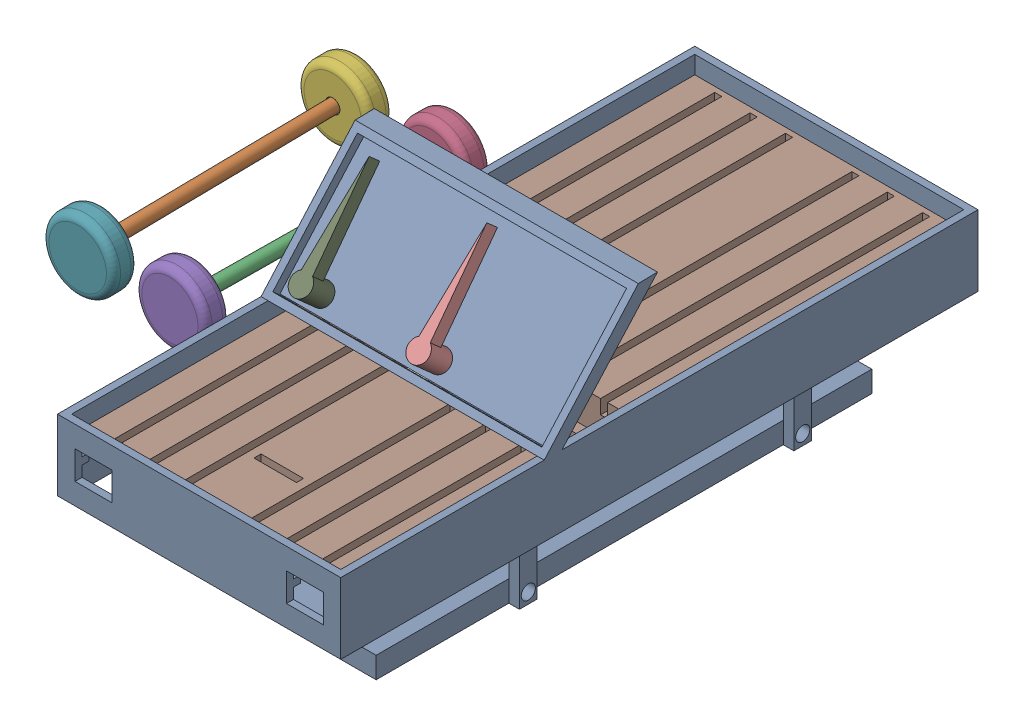
SolidWorks assembly SomeAssemblySmartPorch, configuration Default. Lengths in mm.
Overall size (178.29 89.34 228.6).
10 component instances, 5 part files, 13 mates.
Components (placement in the parent):
- CarBodySmartPorch-1: CarBodySmartPorch [Default] at (-89.7338 -29.1882 67.1813) size (101.6 88.9 228.6)
- AxleSmartPorch-1: AxleSmartPorch [Default] at (-198.0073 -16.2523 -0.0444) x (-0.855372 0.517873 0.012113) z (-0.013035 0.001859 -0.999913) size (4.57 4.57 96.52)
- AxleSmartPorch-2: AxleSmartPorch [Default] at (-163.9538 -16.0285 -96.7463) x (-0.659648 0.751544 -0.006868) z (-0.011251 -0.000737 0.999936) size (4.57 4.57 96.52)
- WheelSmartPorch-1: WheelSmartPorch [Default] at (-164.0253 -16.0332 -90.3967) x (-0.744656 -0.667389 -0.008871) z (0.011251 0.000737 -0.999936) size (25.4 25.4 8.89)
- WheelSmartPorch-2: WheelSmartPorch [Default] at (-164.9684 -16.095 -6.582) x (0.967145 0.253986 0.01107) z (-0.011251 -0.000737 0.999936) size (25.4 25.4 8.89)
- WheelSmartPorch-3: WheelSmartPorch [Default] at (-199.1826 -16.0847 -90.2066) x (-0.750572 0.660697 0.011013) z (-0.013035 0.001859 -0.999913) size (25.4 25.4 8.89)
- WheelSmartPorch-4: WheelSmartPorch [Default] at (-198.09 -16.2405 -6.3939) x (-0.977216 0.211841 0.013133) z (0.013035 -0.001859 0.999913) size (25.4 25.4 8.89)
- WirePassThroughSmartPorch-1: WirePassThroughSmartPorch [Default] at (-90.3688 -15.2182 -47.7537) x (0 0 1) z (0 1 0) size (222.25 95.25 13.97)
- WiperSmartPorch-1: WiperSmartPorch [Default] at (-126.4256 0.2124 -13.6256) x (1 0 0) z (0 0.664475 0.747311) size (7.62 40.64 10.16)
- WiperSmartPorch-2: WiperSmartPorch [Default] at (-84.4349 0.4747 -13.8589) x (1 0 0) z (0 0.664475 0.747311) size (7.62 40.64 10.16)
Mates (geometry in assembly coordinates):
- Coincident1: coincident anti-aligned: plane of AxleSmartPorch-2 through (-165.0398 -16.0997 -0.2324) normal (-0.011251 -0.000737 0.999936); circle of WheelSmartPorch-2
- Concentric1: concentric aligned: cylinder of AxleSmartPorch-2 through (-165.0398 -16.0997 -0.2324) axis (0.011251 0.000737 -0.999936) radius 2.286; cylinder of WheelSmartPorch-2 through (-165.0398 -16.0997 -0.2324) axis (0.011251 0.000737 -0.999936) radius 2.54
- Coincident2: coincident anti-aligned: plane of AxleSmartPorch-1 through (-198.0073 -16.2523 -0.0444) normal (0.013035 -0.001859 0.999913); plane of WheelSmartPorch-4 through (-198.0073 -16.2523 -0.0444) normal (-0.013035 0.001859 -0.999913)
- Concentric2: concentric anti-aligned: cylinder of AxleSmartPorch-1 through (-199.2654 -16.0729 -96.556) axis (0.013035 -0.001859 0.999913) radius 2.286; cylinder of WheelSmartPorch-4 through (-198.0073 -16.2523 -0.0444) axis (-0.013035 0.001859 -0.999913) radius 2.54
- Coincident3: coincident anti-aligned: circle of AxleSmartPorch-1; plane of WheelSmartPorch-3 through (-199.2654 -16.0729 -96.556) normal (0.013035 -0.001859 0.999913)
- Concentric3: concentric aligned: cylinder of AxleSmartPorch-1 through (-199.2654 -16.0729 -96.556) axis (0.013035 -0.001859 0.999913) radius 2.286; cylinder of WheelSmartPorch-3 through (-199.2654 -16.0729 -96.556) axis (0.013035 -0.001859 0.999913) radius 2.54
- Coincident4: coincident anti-aligned: plane of AxleSmartPorch-2 through (-163.9538 -16.0285 -96.7463) normal (0.011251 0.000737 -0.999936); plane of WheelSmartPorch-1 through (-163.9538 -16.0285 -96.7463) normal (-0.011251 -0.000737 0.999936)
- Concentric4: concentric anti-aligned: cylinder of AxleSmartPorch-2 through (-165.0398 -16.0997 -0.2324) axis (0.011251 0.000737 -0.999936) radius 2.286; cylinder of WheelSmartPorch-1 through (-163.9538 -16.0285 -96.7463) axis (-0.011251 -0.000737 0.999936) radius 2.54
- Coincident5: coincident anti-aligned: plane of CarBodySmartPorch-1 through (-89.7338 -56.3333 36.6522) normal (0 0.664475 0.747311); plane of WiperSmartPorch-1 through (-126.4256 0.2124 -13.6256) normal (0 -0.664475 -0.747311)
- Coincident7: coincident anti-aligned: plane of CarBodySmartPorch-1 through (-89.7338 -56.3333 36.6522) normal (0 0.664475 0.747311); plane of WiperSmartPorch-2 through (-84.4349 0.4747 -13.8589) normal (0 -0.664475 -0.747311)
- Coincident8: coincident: plane of CarBodySmartPorch-1 through (-137.9938 -54.5882 -133.4787) normal (1 0 0); plane of WirePassThroughSmartPorch-1 through (-137.9938 -10.1382 68.8511) normal (-1 0 0)
- Coincident9: coincident: plane of CarBodySmartPorch-1 through (-137.9938 -15.2182 62.1013) normal (0 1 0); plane of WirePassThroughSmartPorch-1 through (-90.3688 -15.2182 -42.2739) normal (0 -1 0)
- Coincident10: coincident anti-aligned: plane of CarBodySmartPorch-1 through (-137.9938 -54.5882 -158.8787) normal (0 0 1); plane of WirePassThroughSmartPorch-1 through (-137.9938 -10.1382 -158.8787) normal (0 0 -1)
